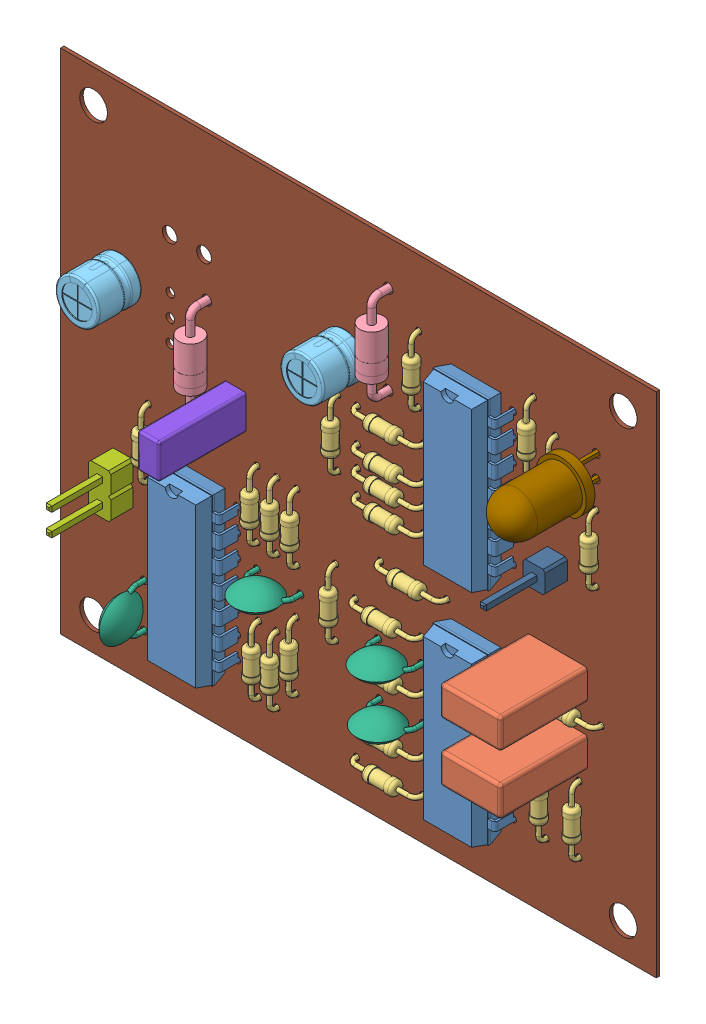
SolidWorks assembly beacondetector-v2, configuration Default. Lengths in mm.
Overall size (68.58 58.42 14.9).
86 component instances, 11 part files, 0 mates.
Components (placement in the parent):
- beacondetector-v2.step-1: beacondetector-v2.step [Default] at origin size (68.58 58.42 14.9)
  - DIP-14_W7.62mm.step-1: DIP-14_W7.62mm.step [Default] at (155.4834 -81.1734 0.45) size (7.87 19.05 6.98)
    - SOLID.step-1: SOLID.step [Default] at origin size (7.87 19.05 6.98)
  - C_Rect_L7.0mm_W3.5mm_P5.00mm.step-1: C_Rect_L7.0mm_W3.5mm_P5.00mm.step [Default] at (170.7134 -110.9234 0.45) x (-1 0 0) z (0 0 1) size (7 3.5 11.9)
    - SOLID-0.step-1: SOLID-0.step [Default] at origin size (7 3.5 11.9)
  - R_Axial_DIN0204_L3.6mm_D1.6mm_P7.62mm_Horizontal.step-1: R_Axial_DIN0204_L3.6mm_D1.6mm_P7.62mm_Horizontal.step [Default] at (166.9134 -121.8634 0.45) x (0 1 0) z (0 0 1) size (8.12 1.6 4.72)
    - SOLID-1.step-1: SOLID-1.step [Default] at origin size (8.12 1.6 4.72)
  - R_Axial_DIN0204_L3.6mm_D1.6mm_P7.62mm_Horizontal.step-2: R_Axial_DIN0204_L3.6mm_D1.6mm_P7.62mm_Horizontal.step [Default] at (145.2234 -95.7984 0.45) size (8.12 1.6 4.72)
    - SOLID-1.step-1: SOLID-1.step [Default] at origin size (8.12 1.6 4.72)
  - D_DO-41_SOD81_P10.16mm_Horizontal.step-1: D_DO-41_SOD81_P10.16mm_Horizontal.step [Default] at (127.8656 -97.897 0.45) x (0 1 0) z (0 0 1) size (10.96 3.14 5.71)
    - SOLID-2.step-1: SOLID-2.step [Default] at origin size (10.96 3.14 5.71)
  - R_Axial_DIN0204_L3.6mm_D1.6mm_P7.62mm_Horizontal.step-3: R_Axial_DIN0204_L3.6mm_D1.6mm_P7.62mm_Horizontal.step [Default] at (145.2034 -89.5984 0.45) size (8.12 1.6 4.72)
    - SOLID-1.step-1: SOLID-1.step [Default] at origin size (8.12 1.6 4.72)
  - R_Axial_DIN0204_L3.6mm_D1.6mm_P7.62mm_Horizontal.step-4: R_Axial_DIN0204_L3.6mm_D1.6mm_P7.62mm_Horizontal.step [Default] at (135.9334 -124.3134 0.45) x (0 1 0) z (0 0 1) size (8.12 1.6 4.72)
    - SOLID-1.step-1: SOLID-1.step [Default] at origin size (8.12 1.6 4.72)
  - R_Axial_DIN0204_L3.6mm_D1.6mm_P7.62mm_Horizontal.step-5: R_Axial_DIN0204_L3.6mm_D1.6mm_P7.62mm_Horizontal.step [Default] at (135.9334 -101.3534 0.45) x (0 -1 0) z (0 0 1) size (8.12 1.6 4.72)
    - SOLID-1.step-1: SOLID-1.step [Default] at origin size (8.12 1.6 4.72)
  - CP_Radial_D5.0mm_P2.50mm.step-1: CP_Radial_D5.0mm_P2.50mm.step [Default] at (143.8434 -86.2984 0.45) x (0 1 0) z (0 0 1) size (6.82 7.94 7)
    - SOLID-3.step-1: SOLID-3.step [Default] at origin size (6.82 7.94 7)
  - R_Axial_DIN0204_L3.6mm_D1.6mm_P7.62mm_Horizontal.step-6: R_Axial_DIN0204_L3.6mm_D1.6mm_P7.62mm_Horizontal.step [Default] at (133.6334 -108.9734 0.45) x (0 1 0) z (0 0 1) size (8.12 1.6 4.72)
    - SOLID-1.step-1: SOLID-1.step [Default] at origin size (8.12 1.6 4.72)
  - R_Axial_DIN0204_L3.6mm_D1.6mm_P7.62mm_Horizontal.step-7: R_Axial_DIN0204_L3.6mm_D1.6mm_P7.62mm_Horizontal.step [Default] at (145.1102 -120.8024 0.45) size (8.12 1.6 4.72)
    - SOLID-1.step-1: SOLID-1.step [Default] at origin size (8.12 1.6 4.72)
  - R_Axial_DIN0204_L3.6mm_D1.6mm_P7.62mm_Horizontal.step-8: R_Axial_DIN0204_L3.6mm_D1.6mm_P7.62mm_Horizontal.step [Default] at (142.6834 -114.2334 0.45) x (0 1 0) z (0 0 1) size (8.12 1.6 4.72)
    - SOLID-1.step-1: SOLID-1.step [Default] at origin size (8.12 1.6 4.72)
  - R_Axial_DIN0204_L3.6mm_D1.6mm_P7.62mm_Horizontal.step-9: R_Axial_DIN0204_L3.6mm_D1.6mm_P7.62mm_Horizontal.step [Default] at (152.8234 -93.4484 0.45) x (-1 0 0) z (0 0 1) size (8.12 1.6 4.72)
    - SOLID-1.step-1: SOLID-1.step [Default] at origin size (8.12 1.6 4.72)
  - R_Axial_DIN0204_L3.6mm_D1.6mm_P7.62mm_Horizontal.step-10: R_Axial_DIN0204_L3.6mm_D1.6mm_P7.62mm_Horizontal.step [Default] at (147.8788 -103.7336 0.45) size (8.12 1.6 4.72)
    - SOLID-1.step-1: SOLID-1.step [Default] at origin size (8.12 1.6 4.72)
  - C_Disc_D5.0mm_W2.5mm_P5.00mm.step-1: C_Disc_D5.0mm_W2.5mm_P5.00mm.step [Default] at (138.6334 -111.6734 0.45) x (-1 0 0) z (0 0 1) size (5.58 2.5 7.49)
    - SOLID-4.step-1: SOLID-4.step [Default] at origin size (5.58 2.5 7.49)
  - R_Axial_DIN0204_L3.6mm_D1.6mm_P7.62mm_Horizontal.step-11: R_Axial_DIN0204_L3.6mm_D1.6mm_P7.62mm_Horizontal.step [Default] at (165.4834 -78.5884 0.45) x (0 -1 0) z (0 0 1) size (8.12 1.6 4.72)
    - SOLID-1.step-1: SOLID-1.step [Default] at origin size (8.12 1.6 4.72)
  - CP_Radial_D5.0mm_P2.50mm.step-2: CP_Radial_D5.0mm_P2.50mm.step [Default] at (117.9656 -91.607 0.45) x (0 1 0) z (0 0 1) size (6.82 7.94 7)
    - SOLID-3.step-1: SOLID-3.step [Default] at origin size (6.82 7.94 7)
  - DIP-14_W7.62mm.step-2: DIP-14_W7.62mm.step [Default] at (155.4834 -106.5734 0.45) size (7.87 19.05 6.98)
    - SOLID.step-1: SOLID.step [Default] at origin size (7.87 19.05 6.98)
  - R_Axial_DIN0204_L3.6mm_D1.6mm_P7.62mm_Horizontal.step-12: R_Axial_DIN0204_L3.6mm_D1.6mm_P7.62mm_Horizontal.step [Default] at (152.7302 -114.5032 0.45) x (-1 0 0) z (0 0 1) size (8.12 1.6 4.72)
    - SOLID-1.step-1: SOLID-1.step [Default] at origin size (8.12 1.6 4.72)
  - R_Axial_DIN0204_L3.6mm_D1.6mm_P7.62mm_Horizontal.step-13: R_Axial_DIN0204_L3.6mm_D1.6mm_P7.62mm_Horizontal.step [Default] at (152.8434 -98.4984 0.45) x (-1 0 0) z (0 0 1) size (8.12 1.6 4.72)
    - SOLID-1.step-1: SOLID-1.step [Default] at origin size (8.12 1.6 4.72)
  - R_Axial_DIN0204_L3.6mm_D1.6mm_P7.62mm_Horizontal.step-14: R_Axial_DIN0204_L3.6mm_D1.6mm_P7.62mm_Horizontal.step [Default] at (172.6692 -86.2584 0.45) x (0 -1 0) z (0 0 1) size (8.12 1.6 4.72)
    - SOLID-1.step-1: SOLID-1.step [Default] at origin size (8.12 1.6 4.72)
  - R_Axial_DIN0204_L3.6mm_D1.6mm_P7.62mm_Horizontal.step-15: R_Axial_DIN0204_L3.6mm_D1.6mm_P7.62mm_Horizontal.step [Default] at (165.6334 -107.4634 0.45) size (8.12 1.6 4.72)
    - SOLID-1.step-1: SOLID-1.step [Default] at origin size (8.12 1.6 4.72)
  - C_Disc_D5.0mm_W2.5mm_P5.00mm.step-2: C_Disc_D5.0mm_W2.5mm_P5.00mm.step [Default] at (147.5834 -111.6234 0.45) size (5.58 2.5 7.49)
    - SOLID-4.step-1: SOLID-4.step [Default] at origin size (5.58 2.5 7.49)
  - PinHeader_1x02_P2.54mm_Vertical.step-1: PinHeader_1x02_P2.54mm_Vertical.step [Default] at (118.1334 -109.0734 0.45) size (2.54 5.08 11.54)
    - SOLID-5.step-1: SOLID-5.step [Default] at origin size (2.54 5.08 11.54)
  - R_Axial_DIN0204_L3.6mm_D1.6mm_P7.62mm_Horizontal.step-16: R_Axial_DIN0204_L3.6mm_D1.6mm_P7.62mm_Horizontal.step [Default] at (133.8334 -116.7134 0.45) x (0 -1 0) z (0 0 1) size (8.12 1.6 4.72)
    - SOLID-1.step-1: SOLID-1.step [Default] at origin size (8.12 1.6 4.72)
  - C_Disc_D5.0mm_W2.5mm_P5.00mm.step-3: C_Disc_D5.0mm_W2.5mm_P5.00mm.step [Default] at (120.6334 -119.2734 0.45) x (0 -1 0) z (0 0 1) size (5.58 2.5 7.49)
    - SOLID-4.step-1: SOLID-4.step [Default] at origin size (5.58 2.5 7.49)
  - R_Axial_DIN0204_L3.6mm_D1.6mm_P7.62mm_Horizontal.step-17: R_Axial_DIN0204_L3.6mm_D1.6mm_P7.62mm_Horizontal.step [Default] at (145.1102 -124.6632 0.45) size (8.12 1.6 4.72)
    - SOLID-1.step-1: SOLID-1.step [Default] at origin size (8.12 1.6 4.72)
  - DIP-14_W7.62mm.step-3: DIP-14_W7.62mm.step [Default] at (123.7334 -106.5734 0.45) size (7.87 19.05 6.98)
    - SOLID.step-1: SOLID.step [Default] at origin size (7.87 19.05 6.98)
  - R_Axial_DIN0204_L3.6mm_D1.6mm_P7.62mm_Horizontal.step-18: R_Axial_DIN0204_L3.6mm_D1.6mm_P7.62mm_Horizontal.step [Default] at (152.2434 -86.2484 0.45) x (0 1 0) z (0 0 1) size (8.12 1.6 4.72)
    - SOLID-1.step-1: SOLID-1.step [Default] at origin size (8.12 1.6 4.72)
  - C_Rect_L4.0mm_W2.5mm_P2.50mm.step-1: C_Rect_L4.0mm_W2.5mm_P2.50mm.step [Default] at (131.1656 -97.897 0.45) x (0 1 0) z (0 0 1) size (4 2.5 11.9)
    - SOLID-6.step-1: SOLID-6.step [Default] at origin size (4 2.5 11.9)
  - R_Axial_DIN0204_L3.6mm_D1.6mm_P7.62mm_Horizontal.step-19: R_Axial_DIN0204_L3.6mm_D1.6mm_P7.62mm_Horizontal.step [Default] at (121.1334 -109.0734 0.45) x (0 1 0) z (0 0 1) size (8.12 1.6 4.72)
    - SOLID-1.step-1: SOLID-1.step [Default] at origin size (8.12 1.6 4.72)
  - LED_D5.0mm.step-1: LED_D5.0mm.step [Default] at (172.6946 -83.1342 0.45) x (0 1 0) z (0 0 1) size (5.4 6.76 14.1)
    - SOLID-7.step-1: SOLID-7.step [Default] at origin size (5.4 6.76 14.1)
  - R_Axial_DIN0204_L3.6mm_D1.6mm_P7.62mm_Horizontal.step-20: R_Axial_DIN0204_L3.6mm_D1.6mm_P7.62mm_Horizontal.step [Default] at (142.9434 -89.5984 0.45) x (0 -1 0) z (0 0 1) size (8.12 1.6 4.72)
    - SOLID-1.step-1: SOLID-1.step [Default] at origin size (8.12 1.6 4.72)
  - C_Disc_D5.0mm_W2.5mm_P5.00mm.step-4: C_Disc_D5.0mm_W2.5mm_P5.00mm.step [Default] at (147.7302 -117.5512 0.45) size (5.58 2.5 7.49)
    - SOLID-4.step-1: SOLID-4.step [Default] at origin size (5.58 2.5 7.49)
  - R_Axial_DIN0204_L3.6mm_D1.6mm_P7.62mm_Horizontal.step-21: R_Axial_DIN0204_L3.6mm_D1.6mm_P7.62mm_Horizontal.step [Default] at (138.1334 -114.1934 0.45) x (0 -1 0) z (0 0 1) size (8.12 1.6 4.72)
    - SOLID-1.step-1: SOLID-1.step [Default] at origin size (8.12 1.6 4.72)
  - C_Rect_L7.0mm_W3.5mm_P5.00mm.step-2: C_Rect_L7.0mm_W3.5mm_P5.00mm.step [Default] at (170.7134 -104.1634 0.45) x (-1 0 0) z (0 0 1) size (7 3.5 11.9)
    - SOLID-0.step-1: SOLID-0.step [Default] at origin size (7 3.5 11.9)
  - R_Axial_DIN0204_L3.6mm_D1.6mm_P7.62mm_Horizontal.step-22: R_Axial_DIN0204_L3.6mm_D1.6mm_P7.62mm_Horizontal.step [Default] at (138.2334 -108.9734 0.45) x (0 1 0) z (0 0 1) size (8.12 1.6 4.72)
    - SOLID-1.step-1: SOLID-1.step [Default] at origin size (8.12 1.6 4.72)
  - R_Axial_DIN0204_L3.6mm_D1.6mm_P7.62mm_Horizontal.step-23: R_Axial_DIN0204_L3.6mm_D1.6mm_P7.62mm_Horizontal.step [Default] at (152.5934 -108.9234 0.45) x (-1 0 0) z (0 0 1) size (8.12 1.6 4.72)
    - SOLID-1.step-1: SOLID-1.step [Default] at origin size (8.12 1.6 4.72)
  - R_Axial_DIN0204_L3.6mm_D1.6mm_P7.62mm_Horizontal.step-24: R_Axial_DIN0204_L3.6mm_D1.6mm_P7.62mm_Horizontal.step [Default] at (168.0434 -81.1784 0.45) x (0 -1 0) z (0 0 1) size (8.12 1.6 4.72)
    - SOLID-1.step-1: SOLID-1.step [Default] at origin size (8.12 1.6 4.72)
  - R_Axial_DIN0204_L3.6mm_D1.6mm_P7.62mm_Horizontal.step-25: R_Axial_DIN0204_L3.6mm_D1.6mm_P7.62mm_Horizontal.step [Default] at (170.7134 -114.2434 0.45) x (0 -1 0) z (0 0 1) size (8.12 1.6 4.72)
    - SOLID-1.step-1: SOLID-1.step [Default] at origin size (8.12 1.6 4.72)
  - D_DO-41_SOD81_P10.16mm_Horizontal.step-2: D_DO-41_SOD81_P10.16mm_Horizontal.step [Default] at (148.7434 -86.2684 0.45) x (0 1 0) z (0 0 1) size (10.96 3.14 5.71)
    - SOLID-2.step-1: SOLID-2.step [Default] at origin size (10.96 3.14 5.71)
  - PinHeader_1x01_P2.54mm_Vertical.step-1: PinHeader_1x01_P2.54mm_Vertical.step [Default] at (168.1434 -93.8984 0.45) size (2.54 2.54 11.54)
    - SOLID-8.step-1: SOLID-8.step [Default] at origin size (2.54 2.54 11.54)
  - beacondetector-v2 PCB.step-1: beacondetector-v2 PCB.step [Default] at origin size (68.58 58.42 0.4)
